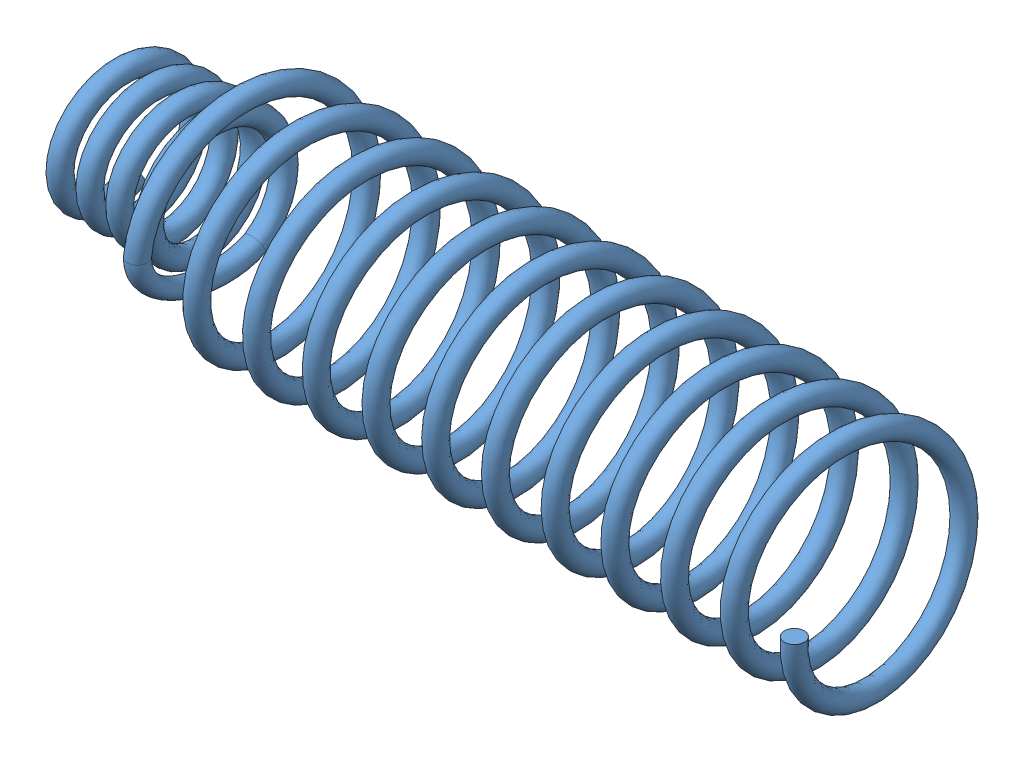
SolidWorks assembly ressorts, configuration Défaut. Lengths in mm.
Overall size (54.76 98.31 12.36).
3 component instances, 3 part files, 0 mates.
Components (placement in the parent):
- ressort2-2: ressort2 [Défaut] at (106.6303 -126.9635 210.4697) x (0 0 1) z (1 0 0) size (6 6.93 15.69)
- ressort3 position fermée-1: ressort3 position fermée [Défaut] at (147.4246 -79.0467 210.9697) x (0 0 -1) z (0.264302 0.96444 0) size (9.52 9.47 31.36)
- ressort6 position fermée-2: ressort6 position fermée [Défaut] at (151.4017 -132.9478 208.4697) x (0.99055 -0.010368 -0.13676) z (-0.010466 -0.999945 0) size (8.58 8.62 23.12)
